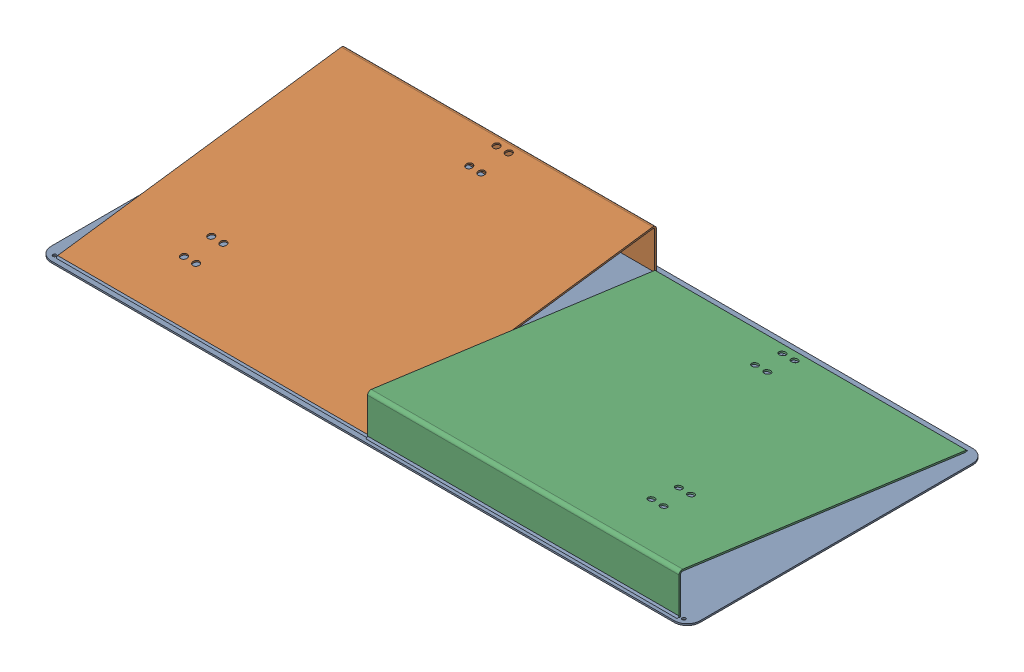
SolidWorks assembly GE-16055_ASM, configuration Default. Lengths in mm.
Overall size (1270 82.09 584.2).
4 component instances, 4 part files, 0 mates.
Components (placement in the parent):
- GE-16055_ASM-1: GE-16055_ASM [Default] at origin size (1219.2 3.17 571.5)
- GE-16016-1: GE-16016 [Default] at origin size (1270 3.17 584.2)
- GE-16056-1: GE-16056 [Default] at (-304.8 3.175 0) size (609.6 78.91 562.4)
- GE-16057-1: GE-16057 [Default] at (304.8 3.175 0) x (-1 0 0) z (0 0 -1) size (609.6 78.91 562.4)
